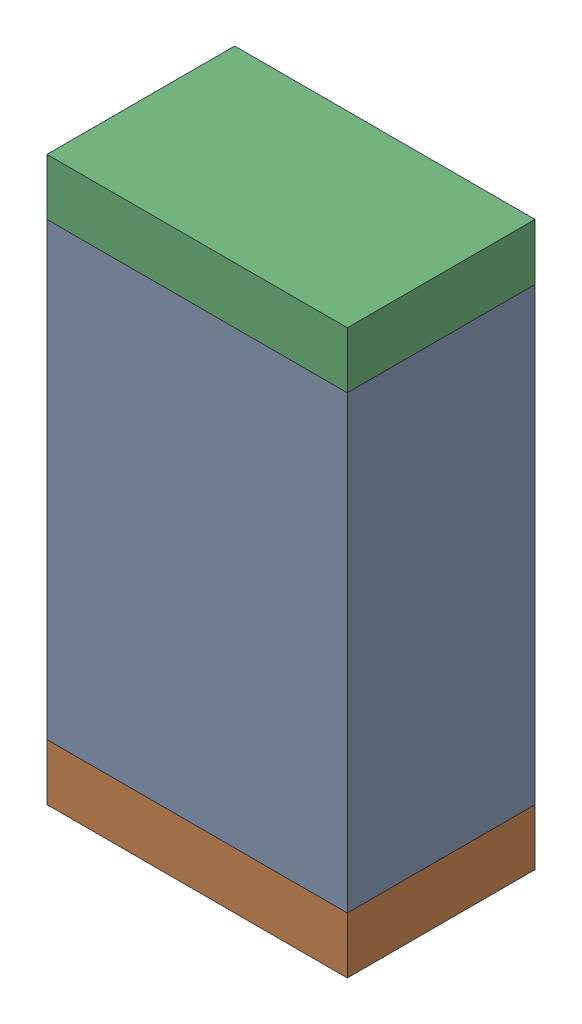
SolidWorks assembly R1, configuration Default. Lengths in mm.
Overall size (0.8 1.5 0.5).
6 component instances, 2 part files, 0 mates.
Components (placement in the parent):
- 810156976-1: 810156976 [Default] at (100.6 6.2 0) size (0.8 1.2 0.5)
  - Extruded_6-1: Extruded_6 [Default] at origin size (0.8 1.2 0.5)
- 810156592-1: 810156592 [Default] at (100.6 5.525 0) size (0.8 0.15 0.5)
  - Extruded_7-1: Extruded_7 [Default] at origin size (0.8 0.15 0.5)
- 810156592-2: 810156592 [Default] at (100.6 6.875 0) size (0.8 0.15 0.5)
  - Extruded_7-1: Extruded_7 [Default] at origin size (0.8 0.15 0.5)
